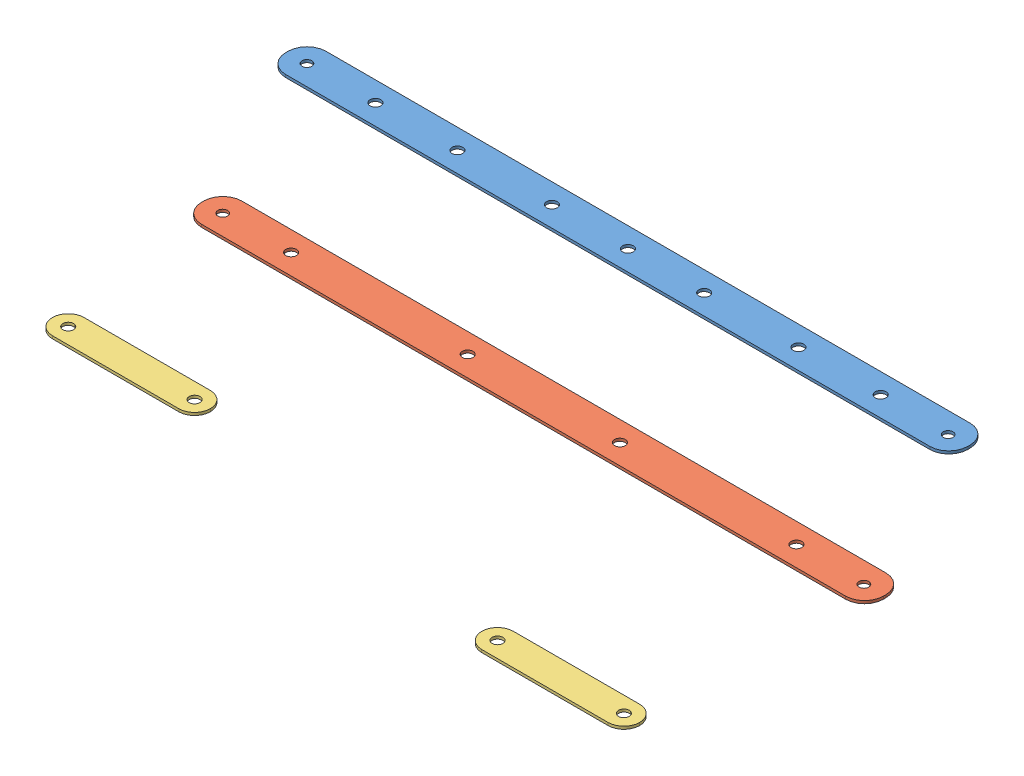
SolidWorks assembly FrontWheelDrive, configuration Default. Lengths in mm.
Overall size (231.17 51.81 88.93).
4 component instances, 3 part files, 0 mates.
Components (placement in the parent):
- frontWheelBar-1: frontWheelBar [Default] at (40.7153 127.2812 177.1273) size (215.9 0.86 12.75)
- frontWheelBarPiece2-1: frontWheelBarPiece2 [Default] at (39.6583 98.5242 202.7473) size (215.9 0.86 12.75)
- frontWheelBarPiece3-1: frontWheelBarPiece3 [Default] at (-57.505 76.33 236.0826) size (50 0.86 10)
- frontWheelBarPiece3-2: frontWheelBarPiece3 [Default] at (96.9945 76.8583 254.6812) size (50 0.86 10)
